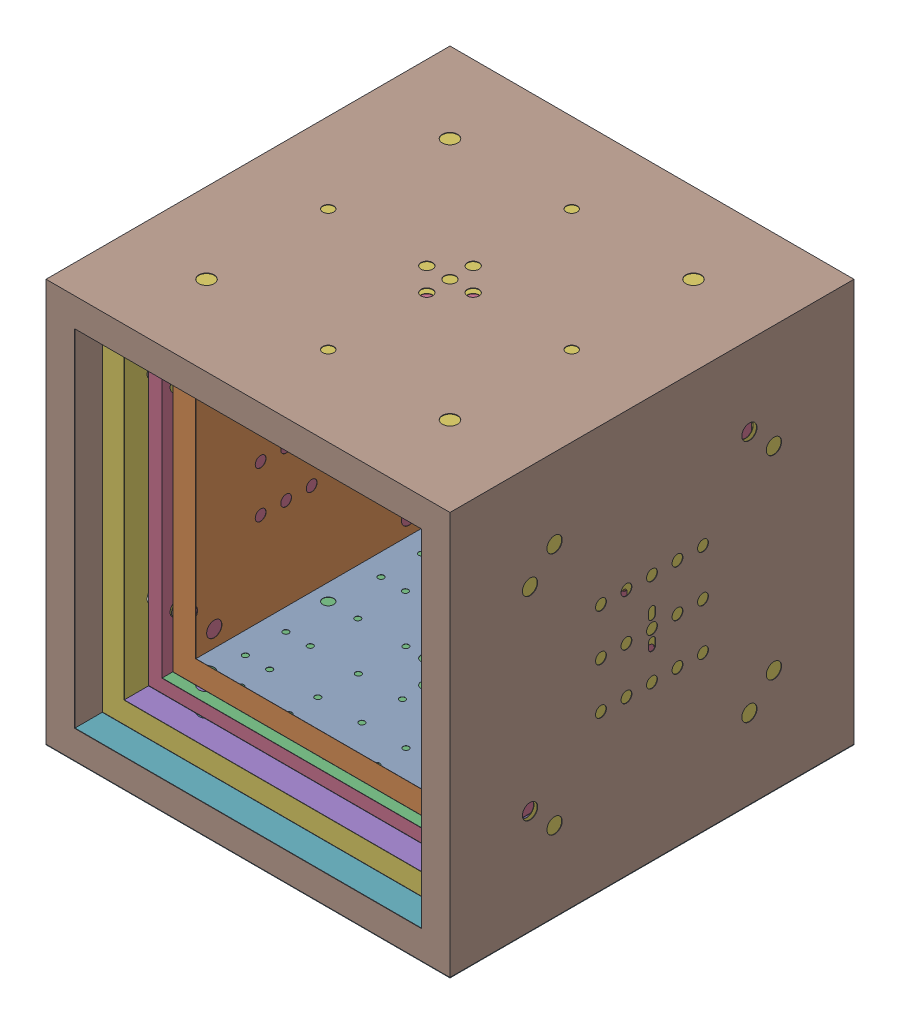
SolidWorks assembly MSR_body, configuration Default. Lengths in mm.
Overall size (3484 3477 3484).
4 component instances, 4 part files, 12 mates.
Components (placement in the parent):
- layer5-1: layer5 [Default] at (0 -1195 0) size (2390 2390 2390)
- layer3-1: layer3 [Default] at (0 -1298.5 0) size (2600 2597 2600)
- layer2-1: layer2 [Default] at (0 0 -1498.5) size (2997 2994 2997)
- layer1-1: layer1 [Default] at (0 0 -1742) size (3484 3477 3484)
Mates (geometry in assembly coordinates):
- Distance3: distance = 1195 mm: plane of assembly through (0 0 0) normal (1 0 0); plane of assembly; plane of layer5-1 through (1195 1195 -1195) normal (1 0 0)
- Distance4: distance = 1195 mm: plane of assembly through (0 0 0) normal (0 1 0); plane of assembly; plane of layer5-1 through (0 1195 0) normal (0 1 0)
- Distance5: distance = 1195 mm: plane of assembly through (0 0 0) normal (0 0 1); plane of assembly; plane of layer5-1 through (-1195 1195 1195) normal (0 0 1)
- Distance6: distance = 1300 mm: plane of assembly through (0 0 0) normal (0 0 1); plane of assembly; plane of layer3-1 through (-1300 1298.5 1300) normal (0 0 1)
- Distance7: distance = 1300 mm: plane of assembly through (0 0 0) normal (1 0 0); plane of assembly; plane of layer3-1 through (1300 1298.5 -1300) normal (1 0 0)
- Distance8: distance = 1298.5 mm: plane of assembly through (0 0 0) normal (0 1 0); plane of assembly; plane of layer3-1 through (0 1298.5 0) normal (0 1 0)
- Distance9: distance = 1498.5 mm: plane of assembly through (0 0 0) normal (1 0 0); plane of assembly; plane of layer2-1 through (1498.5 1497 1498.5) normal (1 0 0)
- Distance11: distance = 1498.5 mm: plane of assembly through (0 0 0) normal (0 0 1); plane of assembly; plane of layer2-1 through (0 0 1498.5) normal (0 0 1)
- Distance12: distance = 1497 mm: plane of assembly through (0 0 0) normal (0 1 0); plane of assembly; plane of layer2-1 through (-1498.5 1497 1498.5) normal (0 1 0)
- Distance13: distance = 1742 mm: plane of assembly through (0 0 0) normal (1 0 0); plane of assembly; plane of layer1-1 through (-1742 1738.5 1742) normal (-1 0 0)
- Distance14: distance = 1742 mm: plane of assembly through (0 0 0) normal (0 0 1); plane of assembly; plane of layer1-1 through (0 0 1742) normal (0 0 1)
- Distance15: distance = 1738.5 mm: plane of assembly through (0 0 0) normal (0 1 0); plane of assembly; plane of layer1-1 through (-1742 1738.5 1742) normal (0 1 0)
